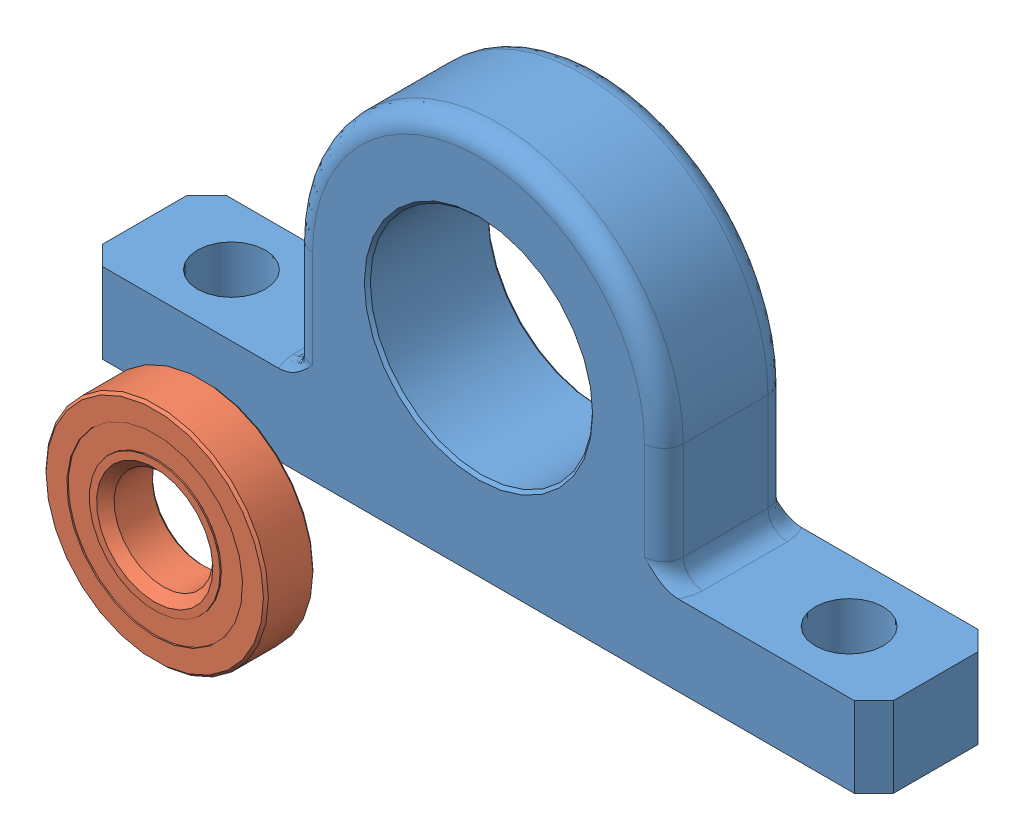
SolidWorks assembly Assem4, configuration Default. Lengths in mm.
Overall size (101.6 49.21 57.47).
2 component instances, 2 part files, 1 mates.
Components (placement in the parent):
- 2.9 3971N196_READY-MOUNT BEARING HOUSING-1: 2.9 3971N196_READY-MOUNT BEARING HOUSING [3971N196] at (32.7528 40.0872 89.5024) size (101.6 49.21 15.88)
- 1.31 bearing 2342K166_PERMANENTLY LUBRICATED BALL BEARING-1: 1.31 bearing 2342K166_PERMANENTLY LUBRICATED BALL BEARING [2342K166] at (32.7528 65.4872 135.8644) x (0.913439 -0.406975 0) z (0 0 1) size (28.57 28.57 6.35)
Mates (geometry in assembly coordinates):
- Concentric1: concentric anti-aligned: cylinder of 2.9 3971N196_READY-MOUNT BEARING HOUSING-1 through (32.7528 65.4872 97.4399) axis (0 0 -1) radius 14.2875; cylinder of 1.31 bearing 2342K166_PERMANENTLY LUBRICATED BALL BEARING-1 through (32.7528 65.4872 139.0394) axis (0 0 1) radius 14.2875
